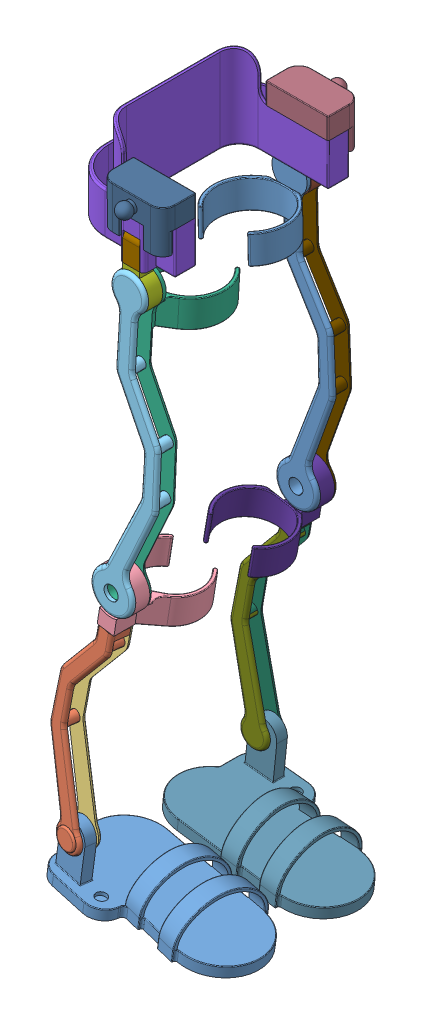
SolidWorks assembly Exoskeleton_C, configuration Default. Lengths in mm.
Overall size (281.88 956.72 336.19).
24 component instances, 19 part files, 0 mates.
Components (placement in the parent):
- FootExo-1: FootExo [Default] at (-2.4183 -802.1093 60.293) x (0.117262 -0.020374 -0.992892) z (0.984918 -0.125692 0.1189) size (153.04 85 257)
- RightKnee^Exoskeleton_C-1: RightKnee^Exoskeleton_C [Default] at origin size (173 395.06 125.09) (virtual)
  - KneeExo1-1: KneeExo1 [Default] at (-5.5057 -745.8048 145.3887) x (0.184994 0.982738 0.001682) z (-0.975719 0.183876 -0.119007) size (330 27.5 75.18)
  - KneeExo2-1: KneeExo2 [Default] at (-2.5742 -746.3142 120.5664) x (0.184994 0.982738 0.001682) z (-0.975719 0.183876 -0.119007) size (310 25 75.18)
  - KneeExo3-1: KneeExo3 [Default] at (58.0411 -411.7866 131) x (-0.157242 -0.98756 0) z (-0.98756 0.157242 0) size (80 120.32 95)
- RightHip^Exoskeleton_C-1: RightHip^Exoskeleton_C [Default] at origin size (134.12 440.78 123.86) (virtual)
  - ThighExo1-1: ThighExo1 [Default] at (58.0411 -411.7866 141) x (0.061249 0.998123 0) z (0.998123 -0.061249 0) size (435 25 85.18)
  - ThighExo2-1: ThighExo2 [Default] at (58.0411 -411.7866 116) x (0.061249 0.998123 0) z (0.998123 -0.061249 0) size (435 118.86 107.68)
- BackExo^Exoskeleton_C-1: BackExo^Exoskeleton_C [Default] at origin size (156.34 175.04 322) (virtual)
  - HipExo-1: HipExo [Default] at (81.3157 -32.5 121) x (0 1 0) z (1 0 0) size (72.5 20 50)
  - BackExo2-1: BackExo2 [Default] at (162.6314 -2.5 66.4286) x (0 0 1) z (-1 0 0) size (282 120.06 156.34)
  - BackExo1-1: BackExo1 [Default] at (81.3157 -2.5 131) x (0 0 -1) z (1 0 0) size (20 40 24)
  - Holder-1: Holder [Default] at (126.3157 37.5 93.541) x (0 0 -1) z (1 0 0) size (67.46 60 89)
  - HipExo_MIR-1: HipExo_MIR [Default] at (49.75 -32.5 -141) x (0 1 0) z (1 0 0) size (72.5 20 50)
  - BackExo1_MIR-1: BackExo1_MIR [Default] at (81.3157 -2.5 -131) x (0 0 1) z (-1 0 0) size (20 40 24)
  - Holder_MIR-1: Holder_MIR [Default] at (126.3157 37.5 -93.541) x (0 0 1) z (-1 0 0) size (67.46 60 89)
- FootExo_MIR-1: FootExo_MIR [Default] at (-2.4183 -802.1093 -60.293) x (0 0 1) z (-0.99466 0.103202 0) size (153.04 85 257)
- LeftKnee^Exoskeleton_C-1: LeftKnee^Exoskeleton_C [Default] at origin size (173.24 395.3 122.21) (virtual)
  - KneeExo1_MIR-1: KneeExo1_MIR [Default] at (-5.5057 -745.8048 -145.3887) x (0.170436 0.985369 0) z (0.985369 -0.170436 0) size (330 27.5 75.18)
  - KneeExo2_MIR-1: KneeExo2_MIR [Default] at (-2.5742 -746.3142 -120.5664) x (0.170436 0.985369 0) z (0.985369 -0.170436 0) size (310 25 75.18)
  - KneeExo3_MIR-1: KneeExo3_MIR [Default] at (58.0411 -411.7866 -131) x (-0.170436 -0.985369 0) z (0.985369 -0.170436 0) size (80 120.32 95)
- LeftHip^Exoskeleton_C-1: LeftHip^Exoskeleton_C [Default] at origin size (117.99 437.44 123.86) (virtual)
  - ThighExo1_MIR-1: ThighExo1_MIR [Default] at (58.0411 -411.7866 -141) x (-0.023771 0.999717 0) z (-0.999717 -0.023771 0) size (435 25 85.18)
  - ThighExo2_MIR-1: ThighExo2_MIR [Default] at (58.0411 -411.7 -116) x (-0.023771 0.999717 0) z (-0.999717 -0.023771 0) size (435 118.86 107.68)
